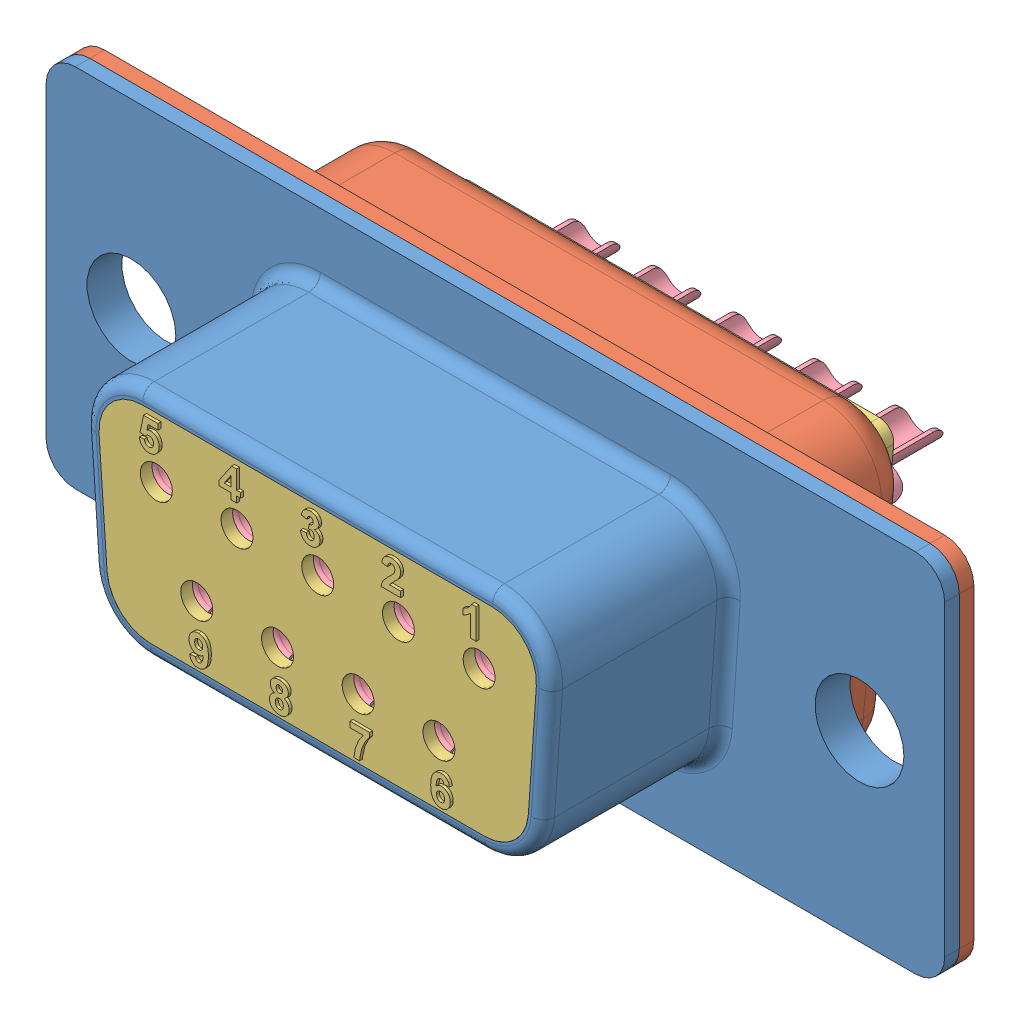
SolidWorks assembly D-tupe 9 pin female, configuration Default. Lengths in mm.
Overall size (30.84 12.55 15.35).
12 component instances, 4 part files, 33 mates.
Components (placement in the parent):
- D-type 2-1: D-type 2 [Default] at (13.8361 17.4152 21.5482) size (30.84 12.55 7.3)
- D-type 1-1: D-type 1 [Default] at (13.8361 17.4152 21.5482) x (-1 0 0) z (0 0 -1) size (30.84 12.55 4.4)
- D-type 3-1: D-type 3 [Default] at (13.8361 17.4152 17.6482) size (16.3 8.2 12.45)
- D-type pin female-1: D-type pin female [Default] at (19.3761 18.8352 27.7482) x (-1 0 0) z (0 0 -1) size (1.6 1.6 14.86)
- D-type pin female-2: D-type pin female [Default] at (16.6061 18.8352 27.7482) x (-1 0 0) z (0 0 -1) size (1.6 1.6 14.86)
- D-type pin female-3: D-type pin female [Default] at (13.8361 18.8352 27.7482) x (-1 0 0) z (0 0 -1) size (1.6 1.6 14.86)
- D-type pin female-4: D-type pin female [Default] at (11.0661 18.8352 27.7482) x (-1 0 0) z (0 0 -1) size (1.6 1.6 14.86)
- D-type pin female-5: D-type pin female [Default] at (8.2961 18.8352 27.7482) x (-1 0 0) z (0 0 -1) size (1.6 1.6 14.86)
- D-type pin female-6: D-type pin female [Default] at (9.6855 15.9952 27.7482) x (1 0 0) z (0 0 -1) size (1.6 1.6 14.86)
- D-type pin female-7: D-type pin female [Default] at (12.4555 15.9952 27.7482) x (1 0 0) z (0 0 -1) size (1.6 1.6 14.86)
- D-type pin female-8: D-type pin female [Default] at (17.9955 15.9952 27.7482) x (1 0 0) z (0 0 -1) size (1.6 1.6 14.86)
- D-type pin female-9: D-type pin female [Default] at (15.2255 15.9952 27.7482) x (1 0 0) z (0 0 -1) size (1.6 1.6 14.86)
Mates (geometry in assembly coordinates):
- Coincident1: coincident anti-aligned: plane of D-type 2-1 through (28.2561 22.6902 21.5482) normal (0 0 -1); plane of D-type 1-1 through (-0.5839 22.6902 21.5482) normal (0 0 1)
- Coincident2: coincident aligned: plane of D-type 2-1 through (29.2561 22.6902 22.0482) normal (1 0 0); plane of D-type 1-1 through (29.2561 22.6902 21.0482) normal (1 0 0)
- Coincident3: coincident: plane of D-type 2-1 through (-0.5839 23.6902 22.0482) normal (0 1 0); line of D-type 1-1 through (-0.5839 23.6902 21.5482) axis (1 0 0)
- Width1: width anti-aligned: plane of D-type 3-1 through (21.1886 21.5152 21.4482) normal (0 1 0); plane of D-type 3-1 through (7.1063 13.3152 21.4482) normal (0 -1 0); plane of D-type 1-1 through (6.4837 21.5652 39.9333) normal (0 -1 0); plane of D-type 1-1 through (20.5659 13.2652 39.9333) normal (0 1 0)
- Width2: width aligned: plane of D-type 3-1 through (5.6872 20.6401 21.4482) normal (-0.99558 -0.093923 0); plane of D-type 3-1 through (21.3624 14.0401 21.4482) normal (0.99558 -0.093923 0); plane of D-type 1-1 through (22.0348 20.6354 39.9333) normal (-0.99558 0.093923 0); plane of D-type 1-1 through (6.2601 14.0354 39.9333) normal (0.99558 0.093923 0)
- Coincident4: coincident anti-aligned: plane of D-type 1-1 through (6.4837 20.7152 17.6482) normal (0 0 1); plane of D-type 3-1 through (21.1886 20.7152 17.6482) normal (0 0 -1)
- Concentric1: concentric aligned: cylinder of D-type 3-1 through (19.3761 18.8352 13.7769) axis (0 0 1) radius 0.75; cylinder of D-type pin female-1 through (19.3761 18.8352 22.6482) axis (0 0 1) radius 0.75
- Coincident8: coincident aligned: plane of D-type 3-1 through (8.1025 15.4402 28.1482) normal (0 0 1); plane of D-type pin female-1 through (19.3761 18.8352 28.1482) normal (0 0 1)
- Concentric2: concentric aligned: cylinder of D-type 3-1 through (16.6061 18.8352 13.7769) axis (0 0 1) radius 0.75; cylinder of D-type pin female-2 through (16.6061 18.8352 22.6482) axis (0 0 1) radius 0.75
- Coincident9: coincident aligned: plane of D-type 3-1 through (8.1025 15.4402 28.1482) normal (0 0 1); plane of D-type pin female-2 through (16.6061 18.8352 28.1482) normal (0 0 1)
- Concentric3: concentric aligned: cylinder of D-type 3-1 through (13.8361 18.8352 13.7769) axis (0 0 1) radius 0.75; cylinder of D-type pin female-3 through (13.8361 18.8352 22.6482) axis (0 0 1) radius 0.75
- Concentric4: concentric aligned: cylinder of D-type 3-1 through (11.0661 18.8352 13.7769) axis (0 0 1) radius 0.75; cylinder of D-type pin female-4 through (11.0661 18.8352 22.6482) axis (0 0 1) radius 0.75
- Concentric5: concentric aligned: cylinder of D-type 3-1 through (8.2961 18.8352 13.7769) axis (0 0 1) radius 0.75; cylinder of D-type pin female-5 through (8.2961 18.8352 22.6482) axis (0 0 1) radius 0.75
- Concentric6: concentric aligned: cylinder of D-type 3-1 through (9.6855 15.9952 13.7769) axis (0 0 1) radius 0.75; cylinder of D-type pin female-6 through (9.6855 15.9952 22.6482) axis (0 0 1) radius 0.75
- Concentric7: concentric aligned: cylinder of D-type 3-1 through (12.4555 15.9952 13.7769) axis (0 0 1) radius 0.75; cylinder of D-type pin female-7 through (12.4555 15.9952 22.6482) axis (0 0 1) radius 0.75
- Concentric8: concentric aligned: cylinder of D-type 3-1 through (15.2255 15.9952 13.7769) axis (0 0 1) radius 0.75; cylinder of D-type pin female-9 through (15.2255 15.9952 22.6482) axis (0 0 1) radius 0.75
- Concentric9: concentric aligned: cylinder of D-type 3-1 through (17.9955 15.9952 13.7769) axis (0 0 1) radius 0.75; cylinder of D-type pin female-8 through (17.9955 15.9952 22.6482) axis (0 0 1) radius 0.75
- Coincident10: coincident aligned: plane of D-type 3-1 through (8.1025 15.4402 28.1482) normal (0 0 1); plane of D-type pin female-3 through (13.8361 18.8352 28.1482) normal (0 0 1)
- Coincident11: coincident aligned: plane of D-type 3-1 through (8.1025 15.4402 28.1482) normal (0 0 1); plane of D-type pin female-4 through (11.0661 18.8352 28.1482) normal (0 0 1)
- Coincident12: coincident aligned: plane of D-type 3-1 through (8.1025 15.4402 28.1482) normal (0 0 1); plane of D-type pin female-5 through (8.2961 18.8352 28.1482) normal (0 0 1)
- Coincident13: coincident aligned: plane of D-type 3-1 through (8.1025 15.4402 28.1482) normal (0 0 1); plane of D-type pin female-6 through (9.6855 15.9952 28.1482) normal (0 0 1)
- Coincident14: coincident aligned: plane of D-type 3-1 through (8.1025 15.4402 28.1482) normal (0 0 1); plane of D-type pin female-7 through (12.4555 15.9952 28.1482) normal (0 0 1)
- Coincident15: coincident aligned: plane of D-type 3-1 through (8.1025 15.4402 28.1482) normal (0 0 1); plane of D-type pin female-8 through (17.9955 15.9952 28.1482) normal (0 0 1)
- Coincident16: coincident aligned: plane of D-type 3-1 through (8.1025 15.4402 28.1482) normal (0 0 1); plane of D-type pin female-9 through (15.2255 15.9952 28.1482) normal (0 0 1)
- Parallel5: parallel anti-aligned: plane of D-type pin female-1 through (19.4061 19.5846 27.9105) normal (-1 0 0); plane of assembly through (0 0 0) normal (1 0 0)
- Parallel6: parallel anti-aligned: plane of D-type pin female-2 through (16.6361 19.5846 27.9105) normal (-1 0 0); plane of assembly through (0 0 0) normal (1 0 0)
- Parallel7: parallel anti-aligned: plane of D-type pin female-3 through (13.8661 19.5846 27.9105) normal (-1 0 0); plane of assembly through (0 0 0) normal (1 0 0)
- Parallel8: parallel anti-aligned: plane of D-type pin female-4 through (11.0961 19.5846 27.9105) normal (-1 0 0); plane of assembly through (0 0 0) normal (1 0 0)
- Parallel9: parallel anti-aligned: plane of D-type pin female-5 through (8.3261 19.5846 27.9105) normal (-1 0 0); plane of assembly through (0 0 0) normal (1 0 0)
- Parallel10: parallel aligned: plane of D-type pin female-6 through (9.6555 15.2458 27.9105) normal (1 0 0); plane of assembly through (0 0 0) normal (1 0 0)
- Parallel11: parallel aligned: plane of D-type pin female-7 through (12.4255 15.2458 27.9105) normal (1 0 0); plane of assembly through (0 0 0) normal (1 0 0)
- Parallel12: parallel aligned: plane of D-type pin female-9 through (15.1955 15.2458 27.9105) normal (1 0 0); plane of assembly through (0 0 0) normal (1 0 0)
- Parallel13: parallel aligned: plane of D-type pin female-8 through (17.9655 15.2458 27.9105) normal (1 0 0); plane of assembly through (0 0 0) normal (1 0 0)
